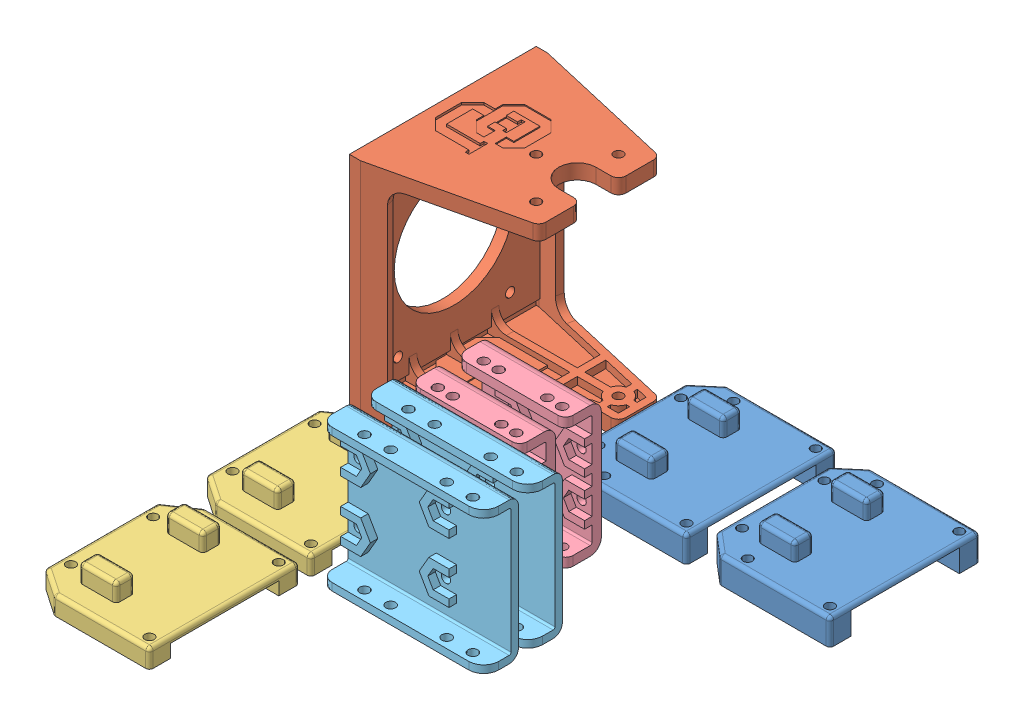
SolidWorks assembly Shapeways Print Assembly, configuration Default. Lengths in mm.
Overall size (118.8 60 136.4).
9 component instances, 5 part files, 25 mates.
Components (placement in the parent):
- Custom Frame - EX 106 to Delrin Plates-1: Custom Frame - EX 106 to Delrin Plates [Default] at origin size (35.4 11.76 40.2)
- Custom Frame - EX 106 to Delrin Plates-2: Custom Frame - EX 106 to Delrin Plates [Default] at (38.4 0 0) size (35.4 11.76 40.2)
- Connector - New Disk to EX 106+-2: Connector - New Disk to EX 106+ [Default] at (-62.7 30 4.9) x (0 -1 0) z (0 0 1) size (60 42 50)
- Custom Frame - RX 64 to Delrin Plates Lower-1: Custom Frame - RX 64 to Delrin Plates Lower [Default] at (-46.25 0 53) size (32.9 9.76 40.2)
- Custom Frame - RX 64 to Delrin Plates Lower-2: Custom Frame - RX 64 to Delrin Plates Lower [Default] at (-46.25 0 96.2) size (32.9 9.76 40.2)
- Custom Frame - RX 28 to Delrin Plates Upper-1: Custom Frame - RX 28 to Delrin Plates Upper [Default] at (-9.3 17.5 28.8625) x (1 0 0) z (0 -1 0) size (29.5 14.36 35)
- Custom Frame - RX 28 to Delrin Plates Upper-2: Custom Frame - RX 28 to Delrin Plates Upper [Default] at (-9.3 17.5 41.125) x (1 0 0) z (0 -1 0) size (29.5 14.36 35)
- Custom Frame - RX 64 to Delrin Plates Upper-1: Custom Frame - RX 64 to Delrin Plates Upper [Default] at (-6.7 19 52.3875) x (-1 0 0) z (0 1 0) size (43.6 14.06 38)
- Custom Frame - RX 64 to Delrin Plates Upper-2: Custom Frame - RX 64 to Delrin Plates Upper [Default] at (-6.7 19 64.15) x (-1 0 0) z (0 1 0) size (43.6 14.06 38)
Mates (geometry in assembly coordinates):
- Coincident4: coincident aligned: plane of Custom Frame - EX 106 to Delrin Plates-1 through (17.7 7 -20.1) normal (0 1 0); plane of Custom Frame - EX 106 to Delrin Plates-2 through (56.1 7 -20.1) normal (0 1 0)
- Coincident5: coincident aligned: plane of Custom Frame - EX 106 to Delrin Plates-1 through (-17.7 7 20.1) normal (0 0 1); plane of Custom Frame - EX 106 to Delrin Plates-2 through (20.7 7 20.1) normal (0 0 1)
- Distance2: distance = 3 mm anti-aligned: plane of Custom Frame - EX 106 to Delrin Plates-2 through (20.7 7 20.1) normal (-1 0 0); plane of Custom Frame - EX 106 to Delrin Plates-1 through (17.7 7 20.1) normal (1 0 0)
- Coincident7: coordinate: point of Custom Frame - EX 106 to Delrin Plates-1; point of assembly
- Coincident8: coincident aligned: plane of Custom Frame - EX 106 to Delrin Plates-1 through (17.7 0 -20.1) normal (0 -1 0); plane of Connector - New Disk to EX 106+-2 through (-26.7 0 4.9) normal (0 -1 0)
- Distance3: distance = 3 mm anti-aligned: plane of Connector - New Disk to EX 106+-2 through (-20.7 0 -11.1) normal (1 0 0); plane of Custom Frame - EX 106 to Delrin Plates-1 through (-17.7 7 20.1) normal (-1 0 0)
- Coincident10: coincident aligned: plane of Custom Frame - EX 106 to Delrin Plates-1 through (-17.7 7 -20.1) normal (0 0 -1); plane of Connector - New Disk to EX 106+-2 through (-59.7 56 -20.1) normal (0 0 -1)
- Coincident11: coincident aligned: plane of Connector - New Disk to EX 106+-2 through (-26.7 0 4.9) normal (0 -1 0); plane of Custom Frame - RX 64 to Delrin Plates Lower-1 through (-29.8 0 32.9) normal (0 -1 0)
- Coincident12: coincident aligned: plane of Connector - New Disk to EX 106+-2 through (-62.7 4 -20.1) normal (-1 0 0); plane of Custom Frame - RX 64 to Delrin Plates Lower-1 through (-62.7 5 73.1) normal (-1 0 0)
- Distance4: distance = 3 mm anti-aligned: plane of Custom Frame - RX 64 to Delrin Plates Lower-1 through (-62.7 5 32.9) normal (0 0 -1); plane of Connector - New Disk to EX 106+-2 through (-59.7 56 29.9) normal (0 0 1)
- Coincident14: coincident aligned: plane of Custom Frame - RX 64 to Delrin Plates Lower-1 through (-29.8 5 32.9) normal (0 1 0); plane of Custom Frame - RX 64 to Delrin Plates Lower-2 through (-29.8 5 76.1) normal (0 1 0)
- Coincident15: coincident aligned: plane of Custom Frame - RX 64 to Delrin Plates Lower-1 through (-62.7 5 73.1) normal (-1 0 0); plane of Custom Frame - RX 64 to Delrin Plates Lower-2 through (-62.7 5 116.3) normal (-1 0 0)
- Distance5: distance = 3 mm anti-aligned: plane of Custom Frame - RX 64 to Delrin Plates Lower-1 through (-62.7 5 73.1) normal (0 0 1); plane of Custom Frame - RX 64 to Delrin Plates Lower-2 through (-62.7 5 76.1) normal (0 0 -1)
- Coincident17: coincident aligned: plane of Connector - New Disk to EX 106+-2 through (-26.7 0 4.9) normal (0 -1 0); plane of Custom Frame - RX 28 to Delrin Plates Upper-1 through (-25.35 0 37.5945) normal (0 -1 0)
- Distance6: distance = 3 mm anti-aligned: plane of Custom Frame - RX 28 to Delrin Plates Upper-1 through (-26.8 3 30.8625) normal (-1 0 0); plane of Custom Frame - RX 64 to Delrin Plates Lower-1 through (-29.8 5 73.1) normal (1 0 0)
- Distance7: distance = 3 mm anti-aligned: plane of Custom Frame - RX 28 to Delrin Plates Upper-1 through (-11.8 7.5 23.1) normal (0 0 -1); plane of Custom Frame - EX 106 to Delrin Plates-1 through (-17.7 7 20.1) normal (0 0 1)
- Distance8: distance = 3 mm: plane of Custom Frame - RX 28 to Delrin Plates Upper-2 through (-11.8 7.5 35.3625) normal (0 0 -1); plane of Custom Frame - RX 28 to Delrin Plates Upper-1 through (2.7 15.975 32.3625) normal (0 0 1)
- Coincident21: coincident: plane of Custom Frame - RX 28 to Delrin Plates Upper-1 through (-26.8 3 30.8625) normal (-1 0 0); plane of Custom Frame - RX 28 to Delrin Plates Upper-2 through (-26.8 3 43.125) normal (-1 0 0)
- Coincident22: coincident aligned: plane of Custom Frame - RX 28 to Delrin Plates Upper-1 through (-25.35 35 30.7305) normal (0 1 0); plane of Custom Frame - RX 28 to Delrin Plates Upper-2 through (-25.35 35 42.993) normal (0 1 0)
- Coincident23: coincident: plane of Custom Frame - RX 28 to Delrin Plates Upper-2 through (-25.35 0 49.857) normal (0 -1 0); plane of Custom Frame - RX 64 to Delrin Plates Upper-1 through (15.52 0 54.7515) normal (0 -1 0)
- Coincident24: coincident: plane of Custom Frame - RX 28 to Delrin Plates Upper-2 through (-26.8 3 43.125) normal (-1 0 0); plane of Custom Frame - RX 64 to Delrin Plates Upper-1 through (-26.8 35.5 54.8875) normal (-1 0 0)
- Distance9: distance = 3 mm anti-aligned: plane of Custom Frame - RX 64 to Delrin Plates Upper-1 through (-9.3 23 47.625) normal (0 0 -1); plane of Custom Frame - RX 28 to Delrin Plates Upper-2 through (2.7 19.025 44.625) normal (0 0 1)
- Distance10: distance = 3 mm: plane of Custom Frame - RX 64 to Delrin Plates Upper-2 through (-9.3 23 59.3875) normal (0 0 -1); plane of Custom Frame - RX 64 to Delrin Plates Upper-1 through (2.2 15.475 56.3875) normal (0 0 1)
- Coincident28: coincident: plane of Custom Frame - RX 64 to Delrin Plates Upper-1 through (15.52 38 61.8235) normal (0 1 0); plane of Custom Frame - RX 64 to Delrin Plates Upper-2 through (15.6532 38 73.586) normal (0 1 0)
- Coincident29: coincident aligned: plane of Custom Frame - RX 64 to Delrin Plates Upper-1 through (16.8 35.5 54.8875) normal (1 0 0); plane of Custom Frame - RX 64 to Delrin Plates Upper-2 through (16.8 35.5 66.65) normal (1 0 0)
